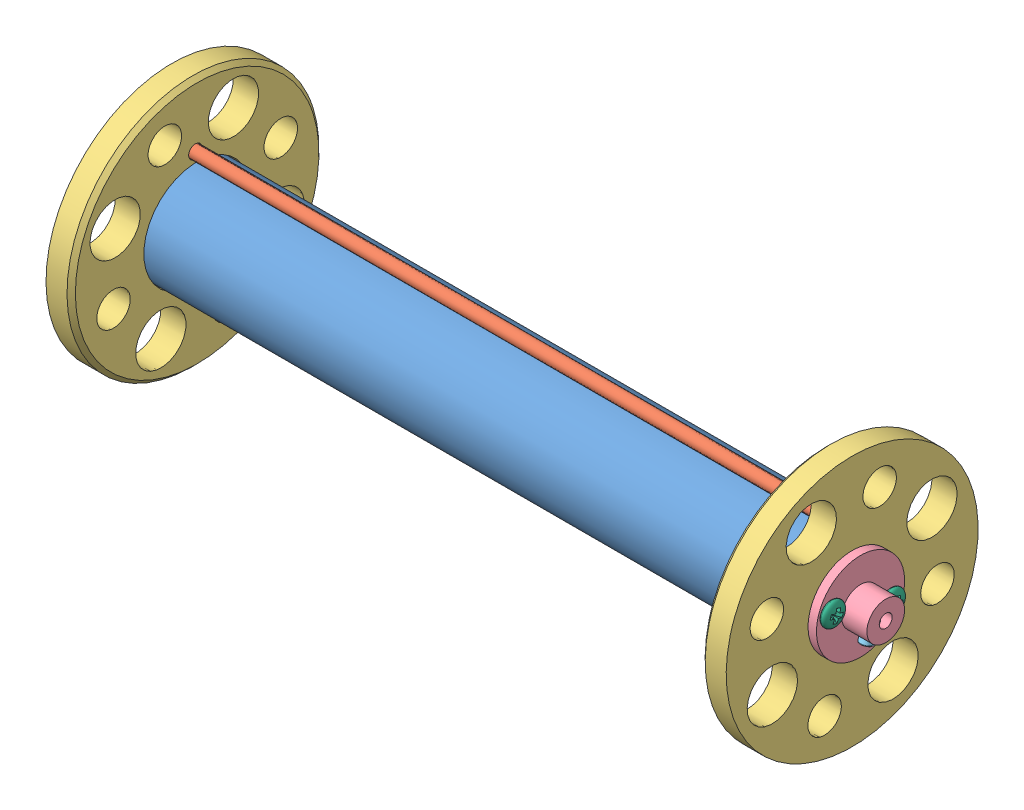
SolidWorks assembly Enrouleur complet, configuration Défaut. Lengths in mm.
Overall size (178 77.58 77.58).
16 component instances, 6 part files, 7 mates.
Components (placement in the parent):
- Tube enrouleur-1: Tube enrouleur [Défaut] at (-79.44 4.4716 0) size (156 25 25)
- Axe acroche volet 156x3-1: Axe acroche volet 156x3 [Défaut] at (-79.44 19.4657 0.4222) size (156 3 3)
- Flasque + bag Arax-1: Flasque + bag Arax [Défaut] at (-75.0264 3.0991 -0.5299) x (1 0 0) z (0 -0.360209 0.932872) size (65.24 60 60)
  - Flasques enrouleur-1: Flasques enrouleur [Défaut] at (-7.4136 1.4712 0) size (6 60 60)
  - Bag ARAX D3 + Vis pointeau-1: Bag ARAX D3 + Vis pointeau [Défaut] at (-11.4136 1.7304 -0.1685) x (0 0 -1) z (1 0 0) size (21 21 8)
    - Bague d'arrêt 3x9x20-1: Bague d'arrêt 3x9x20 [Défaut] at (-0.1685 -0.2592 -4) size (21 21 8)
    - Vis pointeau M3-1: Vis pointeau M3 [Défaut] at (-0.1685 -0.8592 -1) x (-0.990722 0 0.135901) z (0.135901 0 0.990722) size (2.9 5.01 2.9)
  - VIs TC 3 x 6.5-1: VIs TC 3 x 6.5 [Défaut] at (-3.0136 1.4712 -7.5) x (0 1 0) z (0 0 1) size (5.6 8.09 5.6)
  - VIs TC 3 x 6.5-2: VIs TC 3 x 6.5 [Défaut] at (-3.0136 1.4712 7.5) x (0 1 0) z (0 0 1) size (5.6 8.09 5.6)
- Flasque + bag Arax-2: Flasque + bag Arax [Défaut] at (72.1464 3.0715 0.4519) x (-1 0 0) z (0 -0.307141 -0.951664) size (65.24 60 60)
  - Flasques enrouleur-1: Flasques enrouleur [Défaut] at (-7.4136 1.4712 0) size (6 60 60)
  - Bag ARAX D3 + Vis pointeau-1: Bag ARAX D3 + Vis pointeau [Défaut] at (-11.4136 1.7304 -0.1685) x (0 0 -1) z (1 0 0) size (21 21 8)
    - Bague d'arrêt 3x9x20-1: Bague d'arrêt 3x9x20 [Défaut] at (-0.1685 -0.2592 -4) size (21 21 8)
    - Vis pointeau M3-1: Vis pointeau M3 [Défaut] at (-0.1685 -0.8592 -1) x (-0.990722 0 0.135901) z (0.135901 0 0.990722) size (2.9 5.01 2.9)
  - VIs TC 3 x 6.5-1: VIs TC 3 x 6.5 [Défaut] at (-3.0136 1.4712 -7.5) x (0 1 0) z (0 0 1) size (5.6 8.09 5.6)
  - VIs TC 3 x 6.5-2: VIs TC 3 x 6.5 [Défaut] at (-3.0136 1.4712 7.5) x (0 1 0) z (0 0 1) size (5.6 8.09 5.6)
Mates (geometry in assembly coordinates):
- Coïncidente1: coincident anti-aligned: plane of Tube enrouleur-1 through (76.56 4.4716 0) normal (1 0 0); plane of Flasque + bag Arax-2/Flasques enrouleur-1 through (76.56 4.4716 0) normal (-1 0 0)
- Coïncidente2: coincident anti-aligned: axis of Tube enrouleur-1 through (76.56 4.4716 0) axis (-1 0 0); axis of Flasque + bag Arax-2/Flasques enrouleur-1 through (73.56 4.4716 0) axis (1 0 0)
- Coïncidente3: coincident anti-aligned: axis of Axe acroche volet 156x3-1 through (76.36 19.4657 0.4222) axis (-1 0 0); axis of Flasque + bag Arax-1/Flasques enrouleur-1 through (-79.44 19.4657 0.4222) axis (1 0 0)
- Coïncidente4: coincident anti-aligned: plane of Axe acroche volet 156x3-1 through (-79.44 19.4657 0.4222) normal (-1 0 0); plane of Flasque + bag Arax-1/Flasques enrouleur-1 through (-79.44 19.4657 0.4222) normal (1 0 0)
- Coïncidente5: coincident aligned: axis of Tube enrouleur-1 through (76.56 4.4716 0) axis (-1 0 0); axis of Flasque + bag Arax-1/Flasques enrouleur-1 through (-76.44 4.4716 0) axis (-1 0 0)
- Coïncidente6: coincident anti-aligned: plane of Tube enrouleur-1 through (-79.44 4.4716 0) normal (-1 0 0); plane of Flasque + bag Arax-1/Flasques enrouleur-1 through (-79.44 4.4716 0) normal (1 0 0)
- Coïncidente7: coincident aligned: axis of Axe acroche volet 156x3-1 through (76.36 19.4657 0.4222) axis (-1 0 0); axis of Flasque + bag Arax-2/Flasques enrouleur-1 through (76.56 19.4657 0.4222) axis (-1 0 0)
